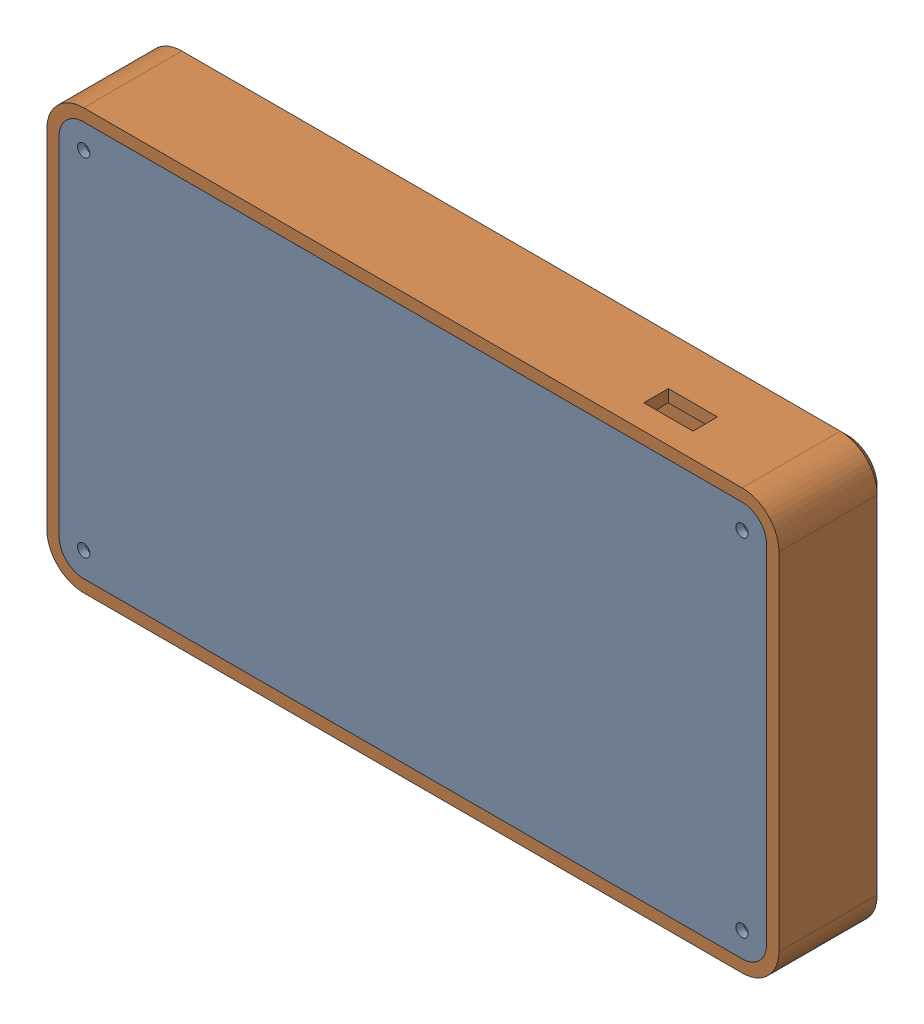
SolidWorks assembly hitbox-assembly, configuration Default. Lengths in mm.
Overall size (298 171 43).
2 component instances, 2 part files, 3 mates.
Components (placement in the parent):
- Backplate-1: Backplate [Default] at (-127.2537 -18.8596 79.963) size (288 161 5)
- Faceplate-1: Faceplate [Default] at (42.7463 16.1404 41.963) x (-1 0 0) z (0 0 -1) size (298 171 43)
Mates (geometry in assembly coordinates):
- Coincident5: coincident anti-aligned: plane of Backplate-1 through (150.7463 132.1404 79.963) normal (0 0 -1); plane of Faceplate-1 through (150.7463 -8.8596 79.963) normal (0 0 1)
- Coincident6: coincident anti-aligned: plane of Backplate-1 through (-127.2537 -8.8596 84.963) normal (-1 0 0); plane of Faceplate-1 through (-127.2537 132.1404 84.963) normal (1 0 0)
- Coincident7: coincident anti-aligned: plane of Backplate-1 through (-117.2537 -18.8596 84.963) normal (0 -1 0); plane of Faceplate-1 through (-117.2537 -18.8596 84.963) normal (0 1 0)
